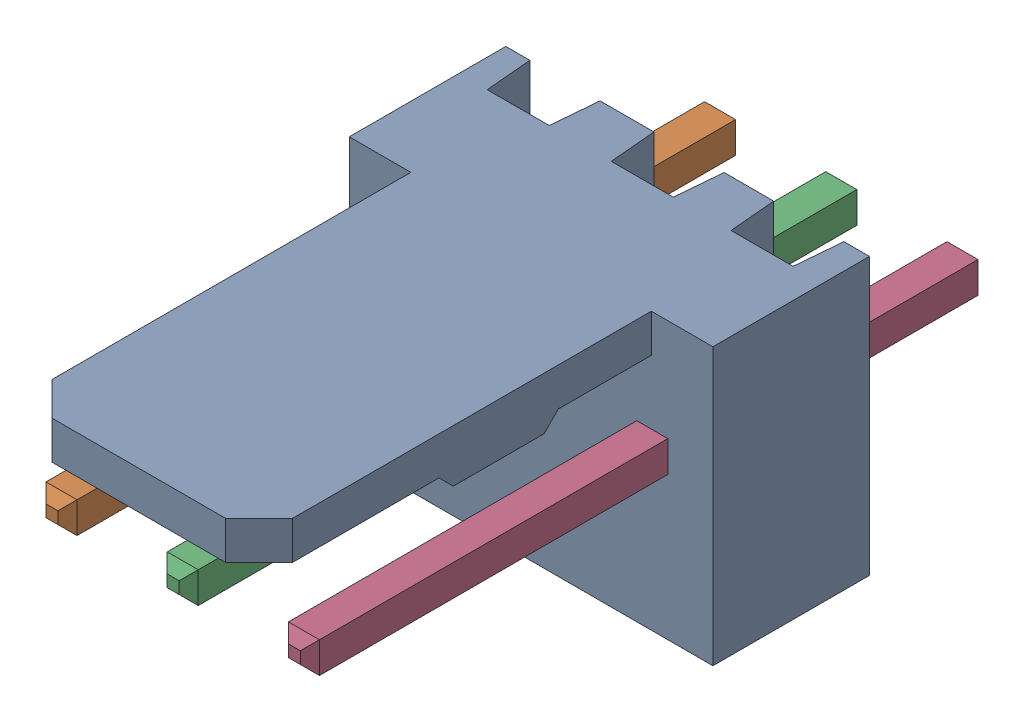
SolidWorks assembly Molex PCB 3 pin v2 v6_2, configuration Default. Lengths in mm.
Overall size (7.62 5.79 14.92).
4 component instances, 2 part files, 0 mates.
Components (placement in the parent):
- BASE9710016 (1)-1: BASE9710016 (1) [Default] at (2.54 2.895 -8.22) size (7.62 5.79 11.5)
- PINO9710016 (1)-1: PINO9710016 (1) [Default] at (1.27 3.325 -0.72) size (0.65 0.65 14.2)
- PINO9710016 (1)-2: PINO9710016 (1) [Default] at (3.81 3.325 -0.72) size (0.65 0.65 14.2)
- PINO9710016 (1)-3: PINO9710016 (1) [Default] at (6.35 3.325 -0.72) size (0.65 0.65 14.2)
